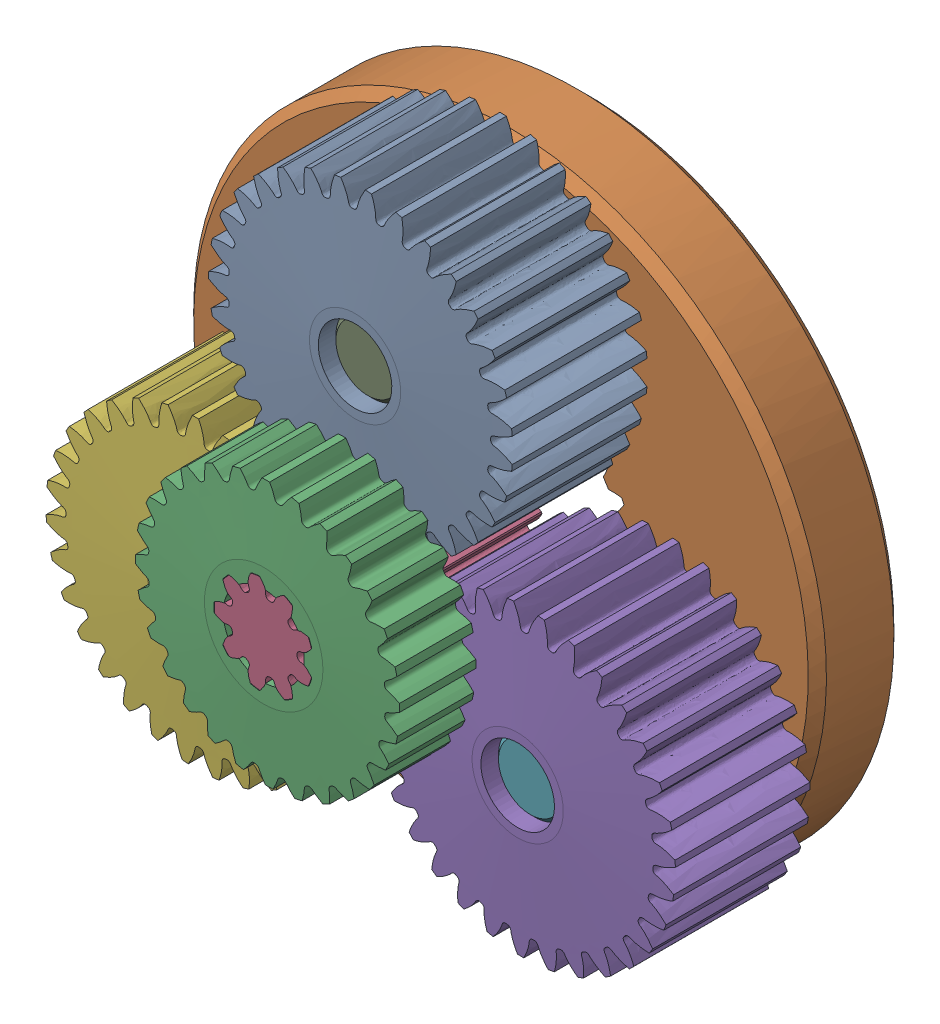
SolidWorks assembly 217-3106-000 Rev2_NO SUN, configuration Default. Lengths in mm.
Overall size (40.34 37.58 17.71).
8 component instances, 4 part files, 0 mates.
Components (placement in the parent):
- 217-3106-002 Rev1_Planet_Revolving_Follower01-1: 217-3106-002 Rev1_Planet_Revolving_Follower01 [Default] at (0 10.2965 6.35) x (0.979503 -0.20143 0) z (0 0 1) size (16.8 16.83 8)
- 217-3106-003 Rev1-1: 217-3106-003 Rev1 [Default] at origin size (34.7 34.7 4.7)
- 217-3106-001 Rev1_Sun_Driver01-1: 217-3106-001 Rev1_Sun_Driver01 [Default] at (0 0 9.0125) x (1 0 0) z (0 0 -1) size (14.56 14.56 12.7)
- 217-3106-002 Rev1_Planet_Revolving_Follower01-2: 217-3106-002 Rev1_Planet_Revolving_Follower01 [Default] at (8.917 -5.1482 6.35) x (-0.664195 -0.74756 0) z (0 0 1) size (16.8 16.83 8)
- 217-3106-002 Rev1_Planet_Revolving_Follower01-3: 217-3106-002 Rev1_Planet_Revolving_Follower01 [Default] at (-8.917 -5.1482 6.35) x (-0.315308 0.948989 0) z (0 0 1) size (16.8 16.83 8)
- 217-2625-010 Rev1-1: 217-2625-010 Rev1 [Default] at (8.917 -5.1482 3.65) x (0.999617 0.027658 0) z (0 0 1) size (4 4 12)
- 217-2625-010 Rev1-2: 217-2625-010 Rev1 [Default] at (-8.917 -5.1482 3.65) x (-0.475856 -0.879523 0) z (0 0 1) size (4 4 12)
- 217-2625-010 Rev1-3: 217-2625-010 Rev1 [Default] at (0 10.2965 3.65) x (-0.523761 0.851865 0) z (0 0 1) size (4 4 12)
